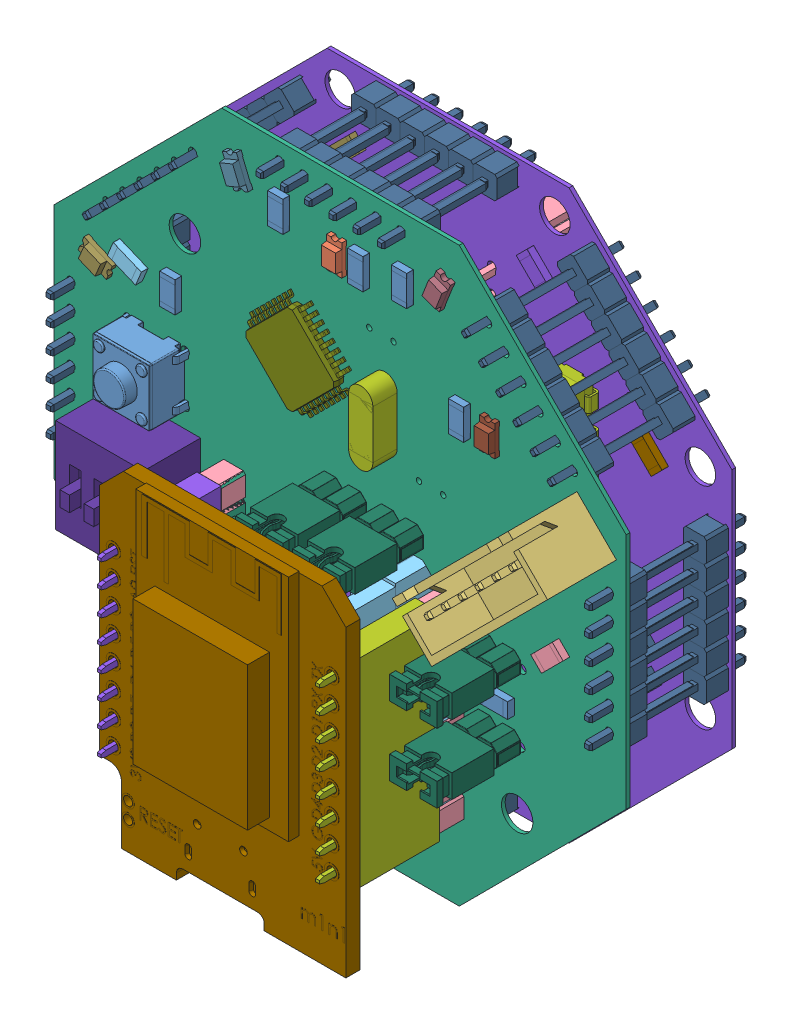
SolidWorks assembly STACK_ASM, configuration Default. Lengths in mm.
Overall size (59.9 59.95 39.03).
236 component instances, 49 part files, 0 mates.
Components (placement in the parent):
- STACK_ASM.step-1: STACK_ASM.step [Default] at origin size (59.9 59.95 39.03)
  - STACK_ASM-asm1.step-1: STACK_ASM-asm1.step [Default] at origin size (59.9 59.95 24.64)
    - STACK_ASM-asm2.step-1: STACK_ASM-asm2.step [Default] at (41.7336 -35.4361 53.84) x (1 0 0) z (0 0 1) size (59.9 59.95 24.64)
      - RPWR.step-1: RPWR.step [Default] at (42.799 44.577 0) x (0 -1 0) z (0 0 1) size (3.2 1.6 0.7)
        - FCR1206J22R.step-1: FCR1206J22R.step [Default] at origin size (3.2 1.6 0.7)
      - RD4.step-1: RD4.step [Default] at (32.258 52.959 0) x (0 -1 0) z (0 0 1) size (3.2 1.6 0.7)
        - FCR1206J22R.step-1: FCR1206J22R.step [Default] at origin size (3.2 1.6 0.7)
      - D4.step-1: D4.step [Default] at (29.845 51.3715 0) x (0 1 0) z (0 0 1) size (3.2 1.6 1.1)
        - User Library-LED 1206 BLUE.step-1: User Library-LED 1206 BLUE.step [Default] at origin size (3.2 1.6 1.1)
      - ISPJ.step-1: ISPJ.step [Default] at (46.1377 31.5327 0) x (0.707107 -0.707107 0) z (0 0 1) size (5.84 17.17 10.21)
        - JST - XH - Thru - 6Pin.step-1: JST - XH - Thru - 6Pin.step [Default] at origin size (5.84 17.17 10.21)
      - ESP.step-1: ESP.step [Default] at (18.796 9.144 0) size (25.8 34.45 18.9)
        - Pin_header_str_1x08_p2_54mm.step-1: Pin_header_str_1x08_p2_54mm.step [Default] at origin size (2.54 20.32 11.54)
          - Pin_header_str_1x08_p2_54mm-0.step-1: Pin_header_str_1x08_p2_54mm-0.step [Default] at (22.8601 17.7801 0) size (2.54 20.32 11.54)
          - Pin_header_str_1x08_p2_54mm-0.step-2: Pin_header_str_1x08_p2_54mm-0.step [Default] at (22.8601 17.7801 0) size (2.54 20.32 11.54)
          - Pin_header_str_1x08_p2_54mm-1.step-1: Pin_header_str_1x08_p2_54mm-1.step [Default] at origin size (2.54 20.32 11.54)
        - Pin_header_str_1x08_p2_54mm-1-2.step-1: Pin_header_str_1x08_p2_54mm-1-2.step [Default] at origin size (2.54 20.32 11.54)
          - Pin_header_str_1x08_p2_54mm-0.step-1: Pin_header_str_1x08_p2_54mm-0.step [Default] at (0.0001 17.7801 0) size (2.54 20.32 11.54)
          - Pin_header_str_1x08_p2_54mm-0.step-2: Pin_header_str_1x08_p2_54mm-0.step [Default] at (0.0001 17.7801 0) size (2.54 20.32 11.54)
          - Pin_header_str_1x08_p2_54mm-3.step-1: Pin_header_str_1x08_p2_54mm-3.step [Default] at origin size (2.54 20.32 11.54)
        - ZL262-8S_P2-54_L20-8_W2-54_H8-5.step-1: ZL262-8S_P2-54_L20-8_W2-54_H8-5.step [Default] at origin size (2.54 20.82 11.5)
        - ZL262-8S_P2-54_L20-8_W2-54_H8-5-4.step-1: ZL262-8S_P2-54_L20-8_W2-54_H8-5-4.step [Default] at origin size (2.54 20.82 11.5)
        - WEMOS-D1-mini_detailed.step-1: WEMOS-D1-mini_detailed.step [Default] at origin size (25.8 34.45 7.6)
      - j5.step-1: j5.step [Default] at (36.322 1.778 0) x (0 -1 0) z (0 0 1) size (2.4 15.24 11.1)
        - 6x_Male_Pin_2.54_mm.step-1: 6x_Male_Pin_2.54_mm.step [Default] at origin size (2.4 15.24 11.1)
          - 1_Male_Pin_2.54_mm.step-1: 1_Male_Pin_2.54_mm.step [Default] at (-0.3249 0.4521 2.5597) x (0 -1 0) z (1 0 0) size (2.54 11.1 2.4)
          - 1_Male_Pin_2.54_mm.step-2: 1_Male_Pin_2.54_mm.step [Default] at (-0.3249 -12.2479 2.5597) x (0 -1 0) z (1 0 0) size (2.54 11.1 2.4)
          - 1_Male_Pin_2.54_mm.step-3: 1_Male_Pin_2.54_mm.step [Default] at (-0.3249 -4.6279 2.5597) x (0 -1 0) z (1 0 0) size (2.54 11.1 2.4)
          - 1_Male_Pin_2.54_mm.step-4: 1_Male_Pin_2.54_mm.step [Default] at (-0.3249 -9.7079 2.5597) x (0 -1 0) z (1 0 0) size (2.54 11.1 2.4)
          - 1_Male_Pin_2.54_mm.step-5: 1_Male_Pin_2.54_mm.step [Default] at (-0.3249 -2.0879 2.5597) x (0 -1 0) z (1 0 0) size (2.54 11.1 2.4)
          - 1_Male_Pin_2.54_mm.step-6: 1_Male_Pin_2.54_mm.step [Default] at (-0.3249 -7.1679 2.5597) x (0 -1 0) z (1 0 0) size (2.54 11.1 2.4)
      - j4.step-1: j4.step [Default] at (58.166 23.622 0) x (-1 0 0) z (0 0 1) size (2.4 15.24 11.1)
        - 6x_Male_Pin_2.54_mm-1.step-1: 6x_Male_Pin_2.54_mm-1.step [Default] at origin size (2.4 15.24 11.1)
          - 1_Male_Pin_2.54_mm.step-1: 1_Male_Pin_2.54_mm.step [Default] at (-0.3249 0.4521 2.5597) x (0 -1 0) z (1 0 0) size (2.54 11.1 2.4)
          - 1_Male_Pin_2.54_mm.step-2: 1_Male_Pin_2.54_mm.step [Default] at (-0.3249 -12.2479 2.5597) x (0 -1 0) z (1 0 0) size (2.54 11.1 2.4)
          - 1_Male_Pin_2.54_mm.step-3: 1_Male_Pin_2.54_mm.step [Default] at (-0.3249 -4.6279 2.5597) x (0 -1 0) z (1 0 0) size (2.54 11.1 2.4)
          - 1_Male_Pin_2.54_mm.step-4: 1_Male_Pin_2.54_mm.step [Default] at (-0.3249 -9.7079 2.5597) x (0 -1 0) z (1 0 0) size (2.54 11.1 2.4)
          - 1_Male_Pin_2.54_mm.step-5: 1_Male_Pin_2.54_mm.step [Default] at (-0.3249 -2.0879 2.5597) x (0 -1 0) z (1 0 0) size (2.54 11.1 2.4)
          - 1_Male_Pin_2.54_mm.step-6: 1_Male_Pin_2.54_mm.step [Default] at (-0.3249 -7.1679 2.5597) x (0 -1 0) z (1 0 0) size (2.54 11.1 2.4)
      - j7.step-1: j7.step [Default] at (45.4191 54.3993 0) x (0.707107 0.707107 0) z (0 0 1) size (2.4 15.24 11.1)
        - 6x_Male_Pin_2.54_mm-2.step-1: 6x_Male_Pin_2.54_mm-2.step [Default] at origin size (2.4 15.24 11.1)
          - 1_Male_Pin_2.54_mm.step-1: 1_Male_Pin_2.54_mm.step [Default] at (-0.3249 0.4521 2.5597) x (0 -1 0) z (1 0 0) size (2.54 11.1 2.4)
          - 1_Male_Pin_2.54_mm.step-2: 1_Male_Pin_2.54_mm.step [Default] at (-0.3249 -12.2479 2.5597) x (0 -1 0) z (1 0 0) size (2.54 11.1 2.4)
          - 1_Male_Pin_2.54_mm.step-3: 1_Male_Pin_2.54_mm.step [Default] at (-0.3249 -4.6279 2.5597) x (0 -1 0) z (1 0 0) size (2.54 11.1 2.4)
          - 1_Male_Pin_2.54_mm.step-4: 1_Male_Pin_2.54_mm.step [Default] at (-0.3249 -9.7079 2.5597) x (0 -1 0) z (1 0 0) size (2.54 11.1 2.4)
          - 1_Male_Pin_2.54_mm.step-5: 1_Male_Pin_2.54_mm.step [Default] at (-0.3249 -2.0879 2.5597) x (0 -1 0) z (1 0 0) size (2.54 11.1 2.4)
          - 1_Male_Pin_2.54_mm.step-6: 1_Male_Pin_2.54_mm.step [Default] at (-0.3249 -7.1679 2.5597) x (0 -1 0) z (1 0 0) size (2.54 11.1 2.4)
      - j6.step-1: j6.step [Default] at (36.322 58.166 0) x (0 -1 0) z (0 0 1) size (2.4 15.24 11.1)
        - 6x_Male_Pin_2.54_mm.step-1: 6x_Male_Pin_2.54_mm.step [Default] at origin size (2.4 15.24 11.1)
          - 1_Male_Pin_2.54_mm.step-1: 1_Male_Pin_2.54_mm.step [Default] at (-0.3249 0.4521 2.5597) x (0 -1 0) z (1 0 0) size (2.54 11.1 2.4)
          - 1_Male_Pin_2.54_mm.step-2: 1_Male_Pin_2.54_mm.step [Default] at (-0.3249 -12.2479 2.5597) x (0 -1 0) z (1 0 0) size (2.54 11.1 2.4)
          - 1_Male_Pin_2.54_mm.step-3: 1_Male_Pin_2.54_mm.step [Default] at (-0.3249 -4.6279 2.5597) x (0 -1 0) z (1 0 0) size (2.54 11.1 2.4)
          - 1_Male_Pin_2.54_mm.step-4: 1_Male_Pin_2.54_mm.step [Default] at (-0.3249 -9.7079 2.5597) x (0 -1 0) z (1 0 0) size (2.54 11.1 2.4)
          - 1_Male_Pin_2.54_mm.step-5: 1_Male_Pin_2.54_mm.step [Default] at (-0.3249 -2.0879 2.5597) x (0 -1 0) z (1 0 0) size (2.54 11.1 2.4)
          - 1_Male_Pin_2.54_mm.step-6: 1_Male_Pin_2.54_mm.step [Default] at (-0.3249 -7.1679 2.5597) x (0 -1 0) z (1 0 0) size (2.54 11.1 2.4)
      - j2.step-1: j2.step [Default] at (14.5249 54.2197 0) x (0.707107 -0.707107 0) z (0 0 1) size (2.4 15.24 11.1)
        - 6x_Male_Pin_2.54_mm-3.step-1: 6x_Male_Pin_2.54_mm-3.step [Default] at origin size (2.4 15.24 11.1)
          - 1_Male_Pin_2.54_mm.step-1: 1_Male_Pin_2.54_mm.step [Default] at (-0.3249 0.4521 2.5597) x (0 -1 0) z (1 0 0) size (2.54 11.1 2.4)
          - 1_Male_Pin_2.54_mm.step-2: 1_Male_Pin_2.54_mm.step [Default] at (-0.3249 -12.2479 2.5597) x (0 -1 0) z (1 0 0) size (2.54 11.1 2.4)
          - 1_Male_Pin_2.54_mm.step-3: 1_Male_Pin_2.54_mm.step [Default] at (-0.3249 -4.6279 2.5597) x (0 -1 0) z (1 0 0) size (2.54 11.1 2.4)
          - 1_Male_Pin_2.54_mm.step-4: 1_Male_Pin_2.54_mm.step [Default] at (-0.3249 -9.7079 2.5597) x (0 -1 0) z (1 0 0) size (2.54 11.1 2.4)
          - 1_Male_Pin_2.54_mm.step-5: 1_Male_Pin_2.54_mm.step [Default] at (-0.3249 -2.0879 2.5597) x (0 -1 0) z (1 0 0) size (2.54 11.1 2.4)
          - 1_Male_Pin_2.54_mm.step-6: 1_Male_Pin_2.54_mm.step [Default] at (-0.3249 -7.1679 2.5597) x (0 -1 0) z (1 0 0) size (2.54 11.1 2.4)
      - j8.step-1: j8.step [Default] at (1.778 23.622 0) x (-1 0 0) z (0 0 1) size (2.4 15.24 11.1)
        - 6x_Male_Pin_2.54_mm-4.step-1: 6x_Male_Pin_2.54_mm-4.step [Default] at origin size (2.4 15.24 11.1)
          - 1_Male_Pin_2.54_mm.step-1: 1_Male_Pin_2.54_mm.step [Default] at (-0.3249 0.4521 2.5597) x (0 -1 0) z (1 0 0) size (2.54 11.1 2.4)
          - 1_Male_Pin_2.54_mm.step-2: 1_Male_Pin_2.54_mm.step [Default] at (-0.3249 -12.2479 2.5597) x (0 -1 0) z (1 0 0) size (2.54 11.1 2.4)
          - 1_Male_Pin_2.54_mm.step-3: 1_Male_Pin_2.54_mm.step [Default] at (-0.3249 -4.6279 2.5597) x (0 -1 0) z (1 0 0) size (2.54 11.1 2.4)
          - 1_Male_Pin_2.54_mm.step-4: 1_Male_Pin_2.54_mm.step [Default] at (-0.3249 -9.7079 2.5597) x (0 -1 0) z (1 0 0) size (2.54 11.1 2.4)
          - 1_Male_Pin_2.54_mm.step-5: 1_Male_Pin_2.54_mm.step [Default] at (-0.3249 -2.0879 2.5597) x (0 -1 0) z (1 0 0) size (2.54 11.1 2.4)
          - 1_Male_Pin_2.54_mm.step-6: 1_Male_Pin_2.54_mm.step [Default] at (-0.3249 -7.1679 2.5597) x (0 -1 0) z (1 0 0) size (2.54 11.1 2.4)
      - PWR.step-1: PWR.step [Default] at (45.8648 42.9895 0) x (0 1 0) z (0 0 1) size (3.2 1.6 1.1)
        - User Library-LED 1206 BLUE-5.step-1: User Library-LED 1206 BLUE-5.step [Default] at origin size (3.2 1.6 1.1)
      - D3.step-1: D3.step [Default] at (6.223 39.624 0) x (-0.92388 0.382683 0) z (0 0 1) size (3.2 1.6 1.1)
        - User Library-LED 1206 BLUE-6.step-1: User Library-LED 1206 BLUE-6.step [Default] at origin size (3.2 1.6 1.1)
      - D2.step-1: D2.step [Default] at (40.132 53.721 0) x (0.366501 0.930418 0) z (0 0 1) size (3.2 1.6 1.1)
        - User Library-LED 1206 BLUE-7.step-1: User Library-LED 1206 BLUE-7.step [Default] at origin size (3.2 1.6 1.1)
      - D1.step-1: D1.step [Default] at (20.066 53.975 0) x (-0.382683 0.92388 0) z (0 0 1) size (3.2 1.6 1.1)
        - User Library-LED 1206 BLUE-8.step-1: User Library-LED 1206 BLUE-8.step [Default] at origin size (3.2 1.6 1.1)
      - ENB.step-1: ENB.step [Default] at (45.085 24.892 0) size (5.08 2.54 11.77)
        - Bauteil4.step-1: Bauteil4.step [Default] at origin size (5.08 2.54 11.77)
      - ENA.step-1: ENA.step [Default] at (45.085 17.653 0) size (5.08 2.54 11.77)
        - Bauteil4.step-1: Bauteil4.step [Default] at origin size (5.08 2.54 11.77)
      - B5.step-1: B5.step [Default] at (31.496 31.1785 0) x (-1 0 0) z (0 0 1) size (5.08 2.54 11.77)
        - Bauteil4.step-1: Bauteil4.step [Default] at origin size (5.08 2.54 11.77)
      - B4.step-1: B4.step [Default] at (37.465 31.1785 0) x (-1 0 0) z (0 0 1) size (5.08 2.54 11.77)
        - Bauteil4.step-1: Bauteil4.step [Default] at origin size (5.08 2.54 11.77)
      - B3.step-1: B3.step [Default] at (22.86 25.146 0) size (5.08 2.54 11.77)
        - Bauteil4.step-1: Bauteil4.step [Default] at origin size (5.08 2.54 11.77)
      - U.step-1: U.step [Default] at (25.908 41.91 0) x (-0.707107 0.707107 0) z (0 0 1) size (9 9 1.2)
        - ATMEGA328P-AU.step-1: ATMEGA328P-AU.step [Default] at origin size (9 9 1.2)
      - SW1.step-1: SW1.step [Default] at (13.335 20.1818 0) x (0 1 0) z (0 0 1) size (9.9 9.18 10.3)
        - a6e-3104.step-1: a6e-3104.step [Default] at origin size (9.9 9.18 10.3)
      - RSW3.step-1: RSW3.step [Default] at (8.255 23.241 0) x (0 1 0) z (0 0 1) size (3.2 1.6 0.7)
        - FCR1206J22R-9.step-1: FCR1206J22R-9.step [Default] at origin size (3.2 1.6 0.7)
      - RSW2.step-1: RSW2.step [Default] at (10.795 23.241 0) x (0 1 0) z (0 0 1) size (3.2 1.6 0.7)
        - FCR1206J22R-9.step-1: FCR1206J22R-9.step [Default] at origin size (3.2 1.6 0.7)
      - RSW1.step-1: RSW1.step [Default] at (13.335 23.241 0) x (0 1 0) z (0 0 1) size (3.2 1.6 0.7)
        - FCR1206J22R-9.step-1: FCR1206J22R-9.step [Default] at origin size (3.2 1.6 0.7)
      - RST_SW.step-1: RST_SW.step [Default] at (7.747 30.988 0) size (7.69 6.01 8.33)
        - tactileswitch-short.step-1: tactileswitch-short.step [Default] at origin size (7.69 6.01 8.33)
      - RS8.step-1: RS8.step [Default] at (45.466 40.386 0) x (0 1 0) z (0 0 1) size (3.2 1.6 0.7)
        - FCR1206J22R-10.step-1: FCR1206J22R-10.step [Default] at origin size (3.2 1.6 0.7)
      - RS7.step-1: RS7.step [Default] at (43.053 40.386 0) x (0 1 0) z (0 0 1) size (3.2 1.6 0.7)
        - FCR1206J22R-10.step-1: FCR1206J22R-10.step [Default] at origin size (3.2 1.6 0.7)
      - RS6.step-1: RS6.step [Default] at (40.767 40.386 0) x (0 1 0) z (0 0 1) size (3.2 1.6 0.7)
        - FCR1206J22R-10.step-1: FCR1206J22R-10.step [Default] at origin size (3.2 1.6 0.7)
      - RS5.step-1: RS5.step [Default] at (38.481 40.386 0) x (0 1 0) z (0 0 1) size (3.2 1.6 0.7)
        - FCR1206J22R-11.step-1: FCR1206J22R-11.step [Default] at origin size (3.2 1.6 0.7)
      - RS4.step-1: RS4.step [Default] at (45.466 45.72 0) x (0 1 0) z (0 0 1) size (3.2 1.6 0.7)
        - FCR1206J22R-10.step-1: FCR1206J22R-10.step [Default] at origin size (3.2 1.6 0.7)
      - RS3.step-1: RS3.step [Default] at (43.053 45.72 0) x (0 1 0) z (0 0 1) size (3.2 1.6 0.7)
        - FCR1206J22R-10.step-1: FCR1206J22R-10.step [Default] at origin size (3.2 1.6 0.7)
      - RS2.step-1: RS2.step [Default] at (40.767 45.72 0) x (0 1 0) z (0 0 1) size (3.2 1.6 0.7)
        - FCR1206J22R-10.step-1: FCR1206J22R-10.step [Default] at origin size (3.2 1.6 0.7)
      - RS1.step-1: RS1.step [Default] at (38.481 45.72 0) x (0 1 0) z (0 0 1) size (3.2 1.6 0.7)
        - FCR1206J22R-11.step-1: FCR1206J22R-11.step [Default] at origin size (3.2 1.6 0.7)
      - RRST.step-1: RRST.step [Default] at (12.573 41.021 0) x (0 1 0) z (0 0 1) size (3.2 1.6 0.7)
        - FCR1206J22R.step-1: FCR1206J22R.step [Default] at origin size (3.2 1.6 0.7)
      - RENB.step-1: RENB.step [Default] at (52.324 27.813 0) x (0.707107 0.707107 0) z (0 0 1) size (3.2 1.6 0.7)
        - FCR1206J22R-12.step-1: FCR1206J22R-12.step [Default] at origin size (3.2 1.6 0.7)
      - RENA.step-1: RENA.step [Default] at (46.609 20.955 0) x (-1 0 0) z (0 0 1) size (3.2 1.6 0.7)
        - FCR1206J22R.step-1: FCR1206J22R.step [Default] at origin size (3.2 1.6 0.7)
      - RD3.step-1: RD3.step [Default] at (8.0722 41.4214 0) x (0.92388 -0.382683 0) z (0 0 1) size (3.2 1.6 0.7)
        - FCR1206J22R-13.step-1: FCR1206J22R-13.step [Default] at origin size (3.2 1.6 0.7)
      - RD2.step-1: RD2.step [Default] at (36.83 53.721 0) x (0 -1 0) z (0 0 1) size (3.2 1.6 0.7)
        - FCR1206J22R.step-1: FCR1206J22R.step [Default] at origin size (3.2 1.6 0.7)
      - RD1.step-1: RD1.step [Default] at (23.876 53.975 0) x (0 1 0) z (0 0 1) size (3.2 1.6 0.7)
        - FCR1206J22R.step-1: FCR1206J22R.step [Default] at origin size (3.2 1.6 0.7)
      - Board.step-1: Board.step [Default] at origin size (59.9 59.95 0.39)
      - X.step-1: X.step [Default] at (34.671 38.227 0) x (0 1 0) z (0 0 1) size (7.62 2.54 2.54)
  - STACK_ASM-asm50.step-1: STACK_ASM-asm50.step [Default] at origin size (59.44 59.44 32.57)
    - STACK_ASM-asm51.step-1: STACK_ASM-asm51.step [Default] at (42.0574 -35.2116 42.5996) x (1 0 0) z (0 0 1) size (59.44 59.44 32.57)
      - Re8.step-1: Re8.step [Default] at (39.243 50.673 0) x (-0.707107 0.707107 0) z (0 0 1) size (3.2 1.6 0.7)
        - FCR1206J22R-14.step-1: FCR1206J22R-14.step [Default] at origin size (3.2 1.6 0.7)
      - Re7.step-1: Re7.step [Default] at (51.1148 39.9442 0) x (0.707107 -0.707107 0) z (0 0 1) size (3.2 1.6 0.7)
        - FCR1206J22R-15.step-1: FCR1206J22R-15.step [Default] at origin size (3.2 1.6 0.7)
      - Re6.step-1: Re6.step [Default] at (50.419 18.669 0) x (0.707107 0.707107 0) z (0 0 1) size (3.2 1.6 0.7)
        - FCR1206J22R-16.step-1: FCR1206J22R-16.step [Default] at origin size (3.2 1.6 0.7)
      - Re5.step-1: Re5.step [Default] at (40.386 6.477 0) x (-0.707107 -0.707107 0) z (0 0 1) size (3.2 1.6 0.7)
        - FCR1206J22R-17.step-1: FCR1206J22R-17.step [Default] at origin size (3.2 1.6 0.7)
      - Re4.step-1: Re4.step [Default] at (19.431 51.689 0) x (0.707107 0.707107 0) z (0 0 1) size (3.2 1.6 0.7)
        - FCR1206J22R-18.step-1: FCR1206J22R-18.step [Default] at origin size (3.2 1.6 0.7)
      - Re3.step-1: Re3.step [Default] at (8.255 40.513 0) x (-0.707107 -0.707107 0) z (0 0 1) size (3.2 1.6 0.7)
        - FCR1206J22R-19.step-1: FCR1206J22R-19.step [Default] at origin size (3.2 1.6 0.7)
      - Re2.step-1: Re2.step [Default] at (7.366 15.24 0) x (-1 0 0) z (0 0 1) size (3.2 1.6 0.7)
        - FCR1206J22R-20.step-1: FCR1206J22R-20.step [Default] at origin size (3.2 1.6 0.7)
      - Re1.step-1: Re1.step [Default] at (19.431 6.858 0) x (0.707107 -0.707107 0) z (0 0 1) size (3.2 1.6 0.7)
        - FCR1206J22R-21.step-1: FCR1206J22R-21.step [Default] at origin size (3.2 1.6 0.7)
      - CN.step-1: CN.step [Default] at (26.2935 31.4959 0) x (0 1 0) z (0 0 1) size (2.54 10.16 11.68)
        - STACK_ASM-prt33.step-1: STACK_ASM-prt33.step [Default] at origin size (2.54 2.54 11.68)
        - STACK_ASM-prt34.step-1: STACK_ASM-prt34.step [Default] at origin size (2.54 2.54 11.68)
        - STACK_ASM-prt35.step-1: STACK_ASM-prt35.step [Default] at origin size (2.54 2.54 11.68)
        - STACK_ASM-prt36.step-1: STACK_ASM-prt36.step [Default] at origin size (2.54 2.54 11.68)
      - RPWR-1.step-1: RPWR-1.step [Default] at (49.784 21.971 0) x (0.707107 0.707107 0) z (0 0 1) size (3.2 1.6 0.7)
        - FCR1206J22R-16.step-1: FCR1206J22R-16.step [Default] at origin size (3.2 1.6 0.7)
      - PWR-1.step-1: PWR-1.step [Default] at (48.895 24.892 0) x (-0.707107 -0.707107 0) z (0 0 1) size (3.2 1.6 1.1)
        - User Library-LED 1206 BLUE-22.step-1: User Library-LED 1206 BLUE-22.step [Default] at origin size (3.2 1.6 1.1)
      - BTR.step-1: BTR.step [Default] at (21.463 28.067 0) size (5.84 7.17 10.21)
        - JST - XH - Thru - 2Pin.step-1: JST - XH - Thru - 2Pin.step [Default] at origin size (5.84 7.17 10.21)
      - MB.step-1: MB.step [Default] at (34.29 35.56 0) x (-1 0 0) z (0 0 1) size (5.84 17.17 10.21)
        - JST - XH - Thru - 6Pin-23.step-1: JST - XH - Thru - 6Pin-23.step [Default] at origin size (5.84 17.17 10.21)
      - MA.step-1: MA.step [Default] at (27.559 35.56 0) x (-1 0 0) z (0 0 1) size (5.84 17.17 10.21)
        - JST - XH - Thru - 6Pin-23.step-1: JST - XH - Thru - 6Pin-23.step [Default] at origin size (5.84 17.17 10.21)
      - L298.step-1: L298.step [Default] at (28.448 27.178 0) size (9.89 20.2 24.98)
        - L298N.step-1: L298N.step [Default] at origin size (9.89 20.2 24.98)
      - D1-1.step-1: D1-1.step [Default] at (14.224 33.02 0) x (0 -1 0) z (0 0 1) size (3.11 5.3 2.43)
        - User Library-Diode SMD 1N4007-1.step-1: User Library-Diode SMD 1N4007-1.step [Default] at origin size (3.11 5.3 2.43)
      - D8.step-1: D8.step [Default] at (43.053 35.052 0) x (0 -1 0) z (0 0 1) size (3.11 5.3 2.43)
        - User Library-Diode SMD 1N4007-1-24.step-1: User Library-Diode SMD 1N4007-1-24.step [Default] at origin size (3.11 5.3 2.43)
      - D7.step-1: D7.step [Default] at (43.053 31.623 0) x (0 -1 0) z (0 0 1) size (3.11 5.3 2.43)
        - User Library-Diode SMD 1N4007-1-24.step-1: User Library-Diode SMD 1N4007-1-24.step [Default] at origin size (3.11 5.3 2.43)
      - D6.step-1: D6.step [Default] at (43.053 41.91 0) x (0 -1 0) z (0 0 1) size (3.11 5.3 2.43)
        - User Library-Diode SMD 1N4007-1-24.step-1: User Library-Diode SMD 1N4007-1-24.step [Default] at origin size (3.11 5.3 2.43)
      - D5.step-1: D5.step [Default] at (43.053 38.481 0) x (0 -1 0) z (0 0 1) size (3.11 5.3 2.43)
        - User Library-Diode SMD 1N4007-1-24.step-1: User Library-Diode SMD 1N4007-1-24.step [Default] at origin size (3.11 5.3 2.43)
      - D4-1.step-1: D4-1.step [Default] at (14.224 20.828 0) x (0 -1 0) z (0 0 1) size (3.11 5.3 2.43)
        - User Library-Diode SMD 1N4007-1.step-1: User Library-Diode SMD 1N4007-1.step [Default] at origin size (3.11 5.3 2.43)
      - D3-1.step-1: D3-1.step [Default] at (14.224 24.892 0) x (0 -1 0) z (0 0 1) size (3.11 5.3 2.43)
        - User Library-Diode SMD 1N4007-1.step-1: User Library-Diode SMD 1N4007-1.step [Default] at origin size (3.11 5.3 2.43)
      - D2-1.step-1: D2-1.step [Default] at (14.224 28.956 0) x (0 -1 0) z (0 0 1) size (3.11 5.3 2.43)
        - User Library-Diode SMD 1N4007-1.step-1: User Library-Diode SMD 1N4007-1.step [Default] at origin size (3.11 5.3 2.43)
      - j8-1.step-1: j8-1.step [Default] at (1.524 23.368 0) size (2.4 15.24 11.1)
        - 6x_Male_Pin_2.54_mm-5.step-1: 6x_Male_Pin_2.54_mm-5.step [Default] at origin size (2.4 15.24 11.1)
          - 1_Male_Pin_2.54_mm.step-1: 1_Male_Pin_2.54_mm.step [Default] at (-0.3249 -0.4521 -2.9508) x (0 1 0) z (1 0 0) size (2.54 11.1 2.4)
          - 1_Male_Pin_2.54_mm.step-2: 1_Male_Pin_2.54_mm.step [Default] at (-0.3249 12.2479 -2.9508) x (0 1 0) z (1 0 0) size (2.54 11.1 2.4)
          - 1_Male_Pin_2.54_mm.step-3: 1_Male_Pin_2.54_mm.step [Default] at (-0.3249 4.6279 -2.9508) x (0 1 0) z (1 0 0) size (2.54 11.1 2.4)
          - 1_Male_Pin_2.54_mm.step-4: 1_Male_Pin_2.54_mm.step [Default] at (-0.3249 9.7079 -2.9508) x (0 1 0) z (1 0 0) size (2.54 11.1 2.4)
          - 1_Male_Pin_2.54_mm.step-5: 1_Male_Pin_2.54_mm.step [Default] at (-0.3249 2.0879 -2.9508) x (0 1 0) z (1 0 0) size (2.54 11.1 2.4)
          - 1_Male_Pin_2.54_mm.step-6: 1_Male_Pin_2.54_mm.step [Default] at (-0.3249 7.1679 -2.9508) x (0 1 0) z (1 0 0) size (2.54 11.1 2.4)
      - j2-1.step-1: j2-1.step [Default] at (14.2709 53.9657 0) x (-0.707107 0.707107 0) z (0 0 1) size (2.4 15.24 11.1)
        - 6x_Male_Pin_2.54_mm-6.step-1: 6x_Male_Pin_2.54_mm-6.step [Default] at origin size (2.4 15.24 11.1)
          - 1_Male_Pin_2.54_mm.step-1: 1_Male_Pin_2.54_mm.step [Default] at (-0.3249 -0.4521 -2.9508) x (0 1 0) z (1 0 0) size (2.54 11.1 2.4)
          - 1_Male_Pin_2.54_mm.step-2: 1_Male_Pin_2.54_mm.step [Default] at (-0.3249 12.2479 -2.9508) x (0 1 0) z (1 0 0) size (2.54 11.1 2.4)
          - 1_Male_Pin_2.54_mm.step-3: 1_Male_Pin_2.54_mm.step [Default] at (-0.3249 4.6279 -2.9508) x (0 1 0) z (1 0 0) size (2.54 11.1 2.4)
          - 1_Male_Pin_2.54_mm.step-4: 1_Male_Pin_2.54_mm.step [Default] at (-0.3249 9.7079 -2.9508) x (0 1 0) z (1 0 0) size (2.54 11.1 2.4)
          - 1_Male_Pin_2.54_mm.step-5: 1_Male_Pin_2.54_mm.step [Default] at (-0.3249 2.0879 -2.9508) x (0 1 0) z (1 0 0) size (2.54 11.1 2.4)
          - 1_Male_Pin_2.54_mm.step-6: 1_Male_Pin_2.54_mm.step [Default] at (-0.3249 7.1679 -2.9508) x (0 1 0) z (1 0 0) size (2.54 11.1 2.4)
      - j6-1.step-1: j6-1.step [Default] at (35.814 57.912 0) x (0 1 0) z (0 0 1) size (2.4 15.24 11.1)
        - 6x_Male_Pin_2.54_mm-7.step-1: 6x_Male_Pin_2.54_mm-7.step [Default] at origin size (2.4 15.24 11.1)
          - 1_Male_Pin_2.54_mm.step-1: 1_Male_Pin_2.54_mm.step [Default] at (-0.3249 -0.4521 -2.9508) x (0 1 0) z (1 0 0) size (2.54 11.1 2.4)
          - 1_Male_Pin_2.54_mm.step-2: 1_Male_Pin_2.54_mm.step [Default] at (-0.3249 12.2479 -2.9508) x (0 1 0) z (1 0 0) size (2.54 11.1 2.4)
          - 1_Male_Pin_2.54_mm.step-3: 1_Male_Pin_2.54_mm.step [Default] at (-0.3249 4.6279 -2.9508) x (0 1 0) z (1 0 0) size (2.54 11.1 2.4)
          - 1_Male_Pin_2.54_mm.step-4: 1_Male_Pin_2.54_mm.step [Default] at (-0.3249 9.7079 -2.9508) x (0 1 0) z (1 0 0) size (2.54 11.1 2.4)
          - 1_Male_Pin_2.54_mm.step-5: 1_Male_Pin_2.54_mm.step [Default] at (-0.3249 2.0879 -2.9508) x (0 1 0) z (1 0 0) size (2.54 11.1 2.4)
          - 1_Male_Pin_2.54_mm.step-6: 1_Male_Pin_2.54_mm.step [Default] at (-0.3249 7.1679 -2.9508) x (0 1 0) z (1 0 0) size (2.54 11.1 2.4)
      - j7-1.step-1: j7-1.step [Default] at (45.1651 54.1453 0) x (-0.707107 -0.707107 0) z (0 0 1) size (2.4 15.24 11.1)
        - 6x_Male_Pin_2.54_mm-8.step-1: 6x_Male_Pin_2.54_mm-8.step [Default] at origin size (2.4 15.24 11.1)
          - 1_Male_Pin_2.54_mm.step-1: 1_Male_Pin_2.54_mm.step [Default] at (-0.3249 -0.4521 -2.9508) x (0 1 0) z (1 0 0) size (2.54 11.1 2.4)
          - 1_Male_Pin_2.54_mm.step-2: 1_Male_Pin_2.54_mm.step [Default] at (-0.3249 12.2479 -2.9508) x (0 1 0) z (1 0 0) size (2.54 11.1 2.4)
          - 1_Male_Pin_2.54_mm.step-3: 1_Male_Pin_2.54_mm.step [Default] at (-0.3249 4.6279 -2.9508) x (0 1 0) z (1 0 0) size (2.54 11.1 2.4)
          - 1_Male_Pin_2.54_mm.step-4: 1_Male_Pin_2.54_mm.step [Default] at (-0.3249 9.7079 -2.9508) x (0 1 0) z (1 0 0) size (2.54 11.1 2.4)
          - 1_Male_Pin_2.54_mm.step-5: 1_Male_Pin_2.54_mm.step [Default] at (-0.3249 2.0879 -2.9508) x (0 1 0) z (1 0 0) size (2.54 11.1 2.4)
          - 1_Male_Pin_2.54_mm.step-6: 1_Male_Pin_2.54_mm.step [Default] at (-0.3249 7.1679 -2.9508) x (0 1 0) z (1 0 0) size (2.54 11.1 2.4)
      - j4-1.step-1: j4-1.step [Default] at (57.912 23.368 0) size (2.4 15.24 11.1)
        - 6x_Male_Pin_2.54_mm-7.step-1: 6x_Male_Pin_2.54_mm-7.step [Default] at origin size (2.4 15.24 11.1)
          - 1_Male_Pin_2.54_mm.step-1: 1_Male_Pin_2.54_mm.step [Default] at (-0.3249 -0.4521 -2.9508) x (0 1 0) z (1 0 0) size (2.54 11.1 2.4)
          - 1_Male_Pin_2.54_mm.step-2: 1_Male_Pin_2.54_mm.step [Default] at (-0.3249 12.2479 -2.9508) x (0 1 0) z (1 0 0) size (2.54 11.1 2.4)
          - 1_Male_Pin_2.54_mm.step-3: 1_Male_Pin_2.54_mm.step [Default] at (-0.3249 4.6279 -2.9508) x (0 1 0) z (1 0 0) size (2.54 11.1 2.4)
          - 1_Male_Pin_2.54_mm.step-4: 1_Male_Pin_2.54_mm.step [Default] at (-0.3249 9.7079 -2.9508) x (0 1 0) z (1 0 0) size (2.54 11.1 2.4)
          - 1_Male_Pin_2.54_mm.step-5: 1_Male_Pin_2.54_mm.step [Default] at (-0.3249 2.0879 -2.9508) x (0 1 0) z (1 0 0) size (2.54 11.1 2.4)
          - 1_Male_Pin_2.54_mm.step-6: 1_Male_Pin_2.54_mm.step [Default] at (-0.3249 7.1679 -2.9508) x (0 1 0) z (1 0 0) size (2.54 11.1 2.4)
      - j5-1.step-1: j5-1.step [Default] at (35.814 1.5835 0) x (0 1 0) z (0 0 1) size (2.4 15.24 11.1)
        - 6x_Male_Pin_2.54_mm-5.step-1: 6x_Male_Pin_2.54_mm-5.step [Default] at origin size (2.4 15.24 11.1)
          - 1_Male_Pin_2.54_mm.step-1: 1_Male_Pin_2.54_mm.step [Default] at (-0.3249 -0.4521 -2.9508) x (0 1 0) z (1 0 0) size (2.54 11.1 2.4)
          - 1_Male_Pin_2.54_mm.step-2: 1_Male_Pin_2.54_mm.step [Default] at (-0.3249 12.2479 -2.9508) x (0 1 0) z (1 0 0) size (2.54 11.1 2.4)
          - 1_Male_Pin_2.54_mm.step-3: 1_Male_Pin_2.54_mm.step [Default] at (-0.3249 4.6279 -2.9508) x (0 1 0) z (1 0 0) size (2.54 11.1 2.4)
          - 1_Male_Pin_2.54_mm.step-4: 1_Male_Pin_2.54_mm.step [Default] at (-0.3249 9.7079 -2.9508) x (0 1 0) z (1 0 0) size (2.54 11.1 2.4)
          - 1_Male_Pin_2.54_mm.step-5: 1_Male_Pin_2.54_mm.step [Default] at (-0.3249 2.0879 -2.9508) x (0 1 0) z (1 0 0) size (2.54 11.1 2.4)
          - 1_Male_Pin_2.54_mm.step-6: 1_Male_Pin_2.54_mm.step [Default] at (-0.3249 7.1679 -2.9508) x (0 1 0) z (1 0 0) size (2.54 11.1 2.4)
      - Board-25.step-1: Board-25.step [Default] at origin size (59.44 59.44 0.39)
      - E4.step-1: E4.step [Default] at (48.8041 43.6519 0) x (-0.707107 0.707107 0) z (0 0 1) size (10.16 2.54 2.5)
      - E2.step-1: E2.step [Default] at (11.1579 43.4159 0) x (0.707107 0.707107 0) z (0 0 1) size (10.16 2.54 2.5)
      - E3.step-1: E3.step [Default] at (43.416 9.3799 0) x (0.707107 0.707107 0) z (0 0 1) size (10.16 2.54 2.5)
      - E1.step-1: E1.step [Default] at (16.5461 9.3799 0) x (-0.707107 0.707107 0) z (0 0 1) size (10.16 2.54 2.5)
      - C.step-1: C.step [Default] at (16.9909 39.8509 0) x (0.707107 0.707107 0) z (0 0 1) size (8 8 11.5)
